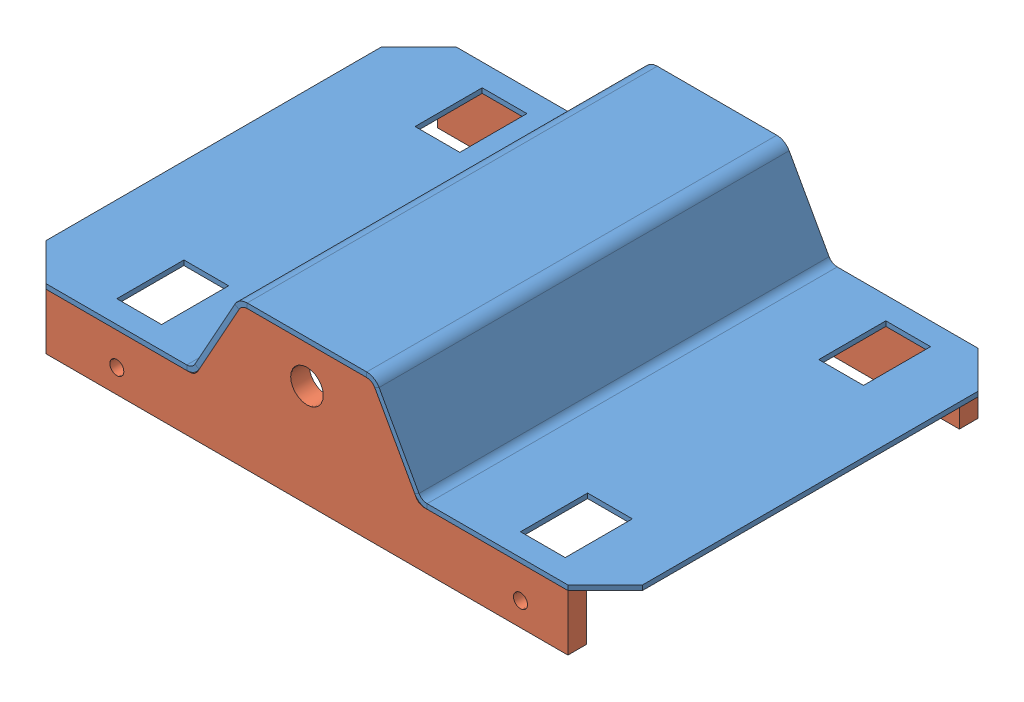
SolidWorks assembly DIAGNOSTIC, DYNO, CHASSIS, TOP ASSY, configuration Default. Lengths in mm.
Overall size (203.2 49.28 139.7).
3 component instances, 2 part files, 6 mates.
Components (placement in the parent):
- DIAGNOSTIC, DYNO, TOP Cover-1: DIAGNOSTIC, DYNO, TOP Cover [Default] at (-3.5138 16.2458 -19.4505) size (203.2 30.23 139.7)
- DIAGNOSTIC, DYNO, PLATE, Sidewall-1: DIAGNOSTIC, DYNO, PLATE, Sidewall [Default] at (-3.5138 16.2458 47.2245) size (177.8 47.62 6.35)
- DIAGNOSTIC, DYNO, PLATE, Sidewall-2: DIAGNOSTIC, DYNO, PLATE, Sidewall [Default] at (-3.5138 16.2458 -86.1255) size (177.8 47.62 6.35)
Mates (geometry in assembly coordinates):
- Coincident1: coincident aligned: plane of DIAGNOSTIC, DYNO, PLATE, Sidewall-1 through (-3.5138 16.2458 47.2245) normal (1 0 0); plane of DIAGNOSTIC, DYNO, PLATE, Sidewall-2 through (-3.5138 16.2458 -86.1255) normal (1 0 0)
- Coincident2: coincident aligned: plane of DIAGNOSTIC, DYNO, TOP Cover-1 through (-3.5138 16.2458 -19.4505) normal (1 0 0); plane of DIAGNOSTIC, DYNO, PLATE, Sidewall-1 through (-3.5138 16.2458 47.2245) normal (1 0 0)
- Coincident3: coincident aligned: plane of DIAGNOSTIC, DYNO, TOP Cover-1 through (-3.5138 16.2458 -19.4505) normal (0 1 0); plane of DIAGNOSTIC, DYNO, PLATE, Sidewall-1 through (-3.5138 16.2458 47.2245) normal (0 1 0)
- Coincident4: coincident aligned: plane of DIAGNOSTIC, DYNO, PLATE, Sidewall-1 through (-3.5138 16.2458 47.2245) normal (0 1 0); plane of DIAGNOSTIC, DYNO, PLATE, Sidewall-2 through (-3.5138 16.2458 -86.1255) normal (0 1 0)
- Coincident5: coincident aligned: plane of DIAGNOSTIC, DYNO, TOP Cover-1 through (-23.8706 46.4718 50.3995) normal (0 0 1); plane of DIAGNOSTIC, DYNO, PLATE, Sidewall-1 through (36.4544 19.4208 50.3995) normal (0 0 1)
- Coincident6: coincident aligned: plane of DIAGNOSTIC, DYNO, TOP Cover-1 through (16.843 46.4718 -89.3005) normal (0 0 -1); plane of DIAGNOSTIC, DYNO, PLATE, Sidewall-2 through (36.4544 19.4208 -89.3005) normal (0 0 -1)
